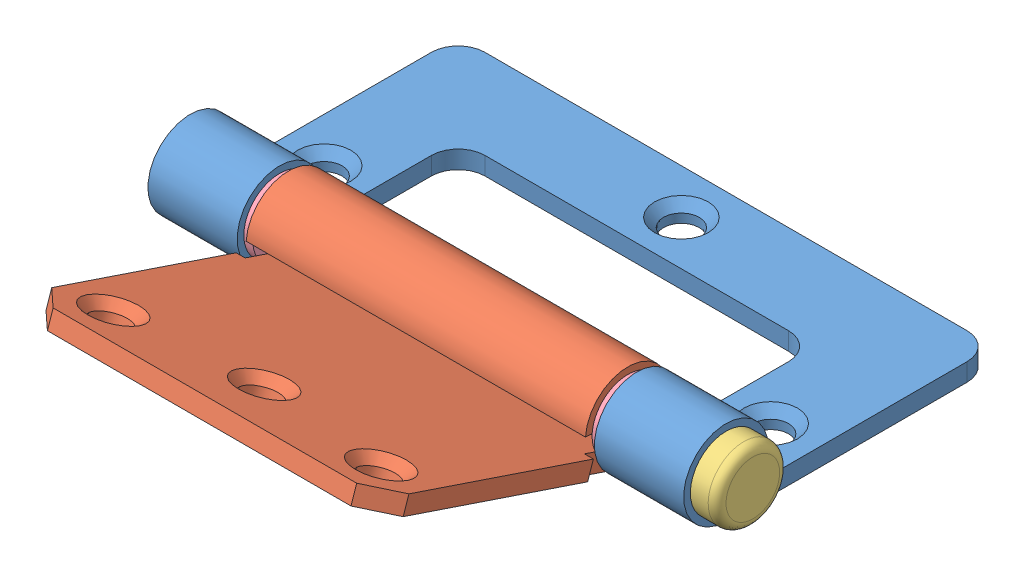
SolidWorks assembly Assembled, configuration Default. Lengths in mm.
Overall size (63 19.77 59).
5 component instances, 4 part files, 9 mates.
Components (placement in the parent):
- 1.Hinge A-1: 1.Hinge A [Default] at (21.0081 35.7241 39.5464) size (60 9.5 34.75)
- 2.Hinge B-1: 2.Hinge B [Default] at (21.0081 40.4917 69.1663) x (-1 0 0) z (0 -0.318898 -0.947789) size (40 9.5 33.75)
- 4.Pin-1: 4.Pin [Default] at (-8.9919 38.4741 54.5464) x (0 0.999658 -0.026144) z (0 -0.026144 -0.999658) size (8 63 8)
- 3.Washer-9: 3.Washer [Default] at (2.0081 38.4741 54.5464) x (0 0.954216 -0.299118) z (0 0.299118 0.954216) size (8 1 8)
- 3.Washer-10: 3.Washer [Default] at (41.0081 38.4741 54.5464) x (0 0.989572 -0.144041) z (0 0.144041 0.989572) size (8 1 8)
Mates (geometry in assembly coordinates):
- Concentric1: concentric anti-aligned: cylinder of 1.Hinge A-1 through (51.0081 38.4741 54.5464) axis (1 0 0) radius 2.75; cylinder of 2.Hinge B-1 through (2.0081 38.4741 54.5464) axis (-1 0 0) radius 2.75
- Width1: width anti-aligned: plane of 1.Hinge A-1 through (51.0081 33.7241 54.5464) normal (1 0 0); plane of 2.Hinge B-1 through (-8.9919 33.7241 54.5464) normal (-1 0 0); plane of 1.Hinge A-1 through (41.0081 33.9721 56.0611) normal (1 0 0); plane of 2.Hinge B-1 through (1.0081 33.9721 56.0611) normal (-1 0 0)
- Concentric2: concentric anti-aligned: cylinder of 1.Hinge A-1 through (51.0081 38.4741 54.5464) axis (1 0 0) radius 2.75; cylinder of 4.Pin-1 through (-8.9919 38.4741 54.5464) axis (-1 0 0) radius 2.75
- Coincident2: coincident anti-aligned: plane of 1.Hinge A-1 through (51.0081 38.4741 54.5464) normal (1 0 0); plane of 4.Pin-1 through (51.0081 34.4755 54.6509) normal (-1 0 0)
- Concentric5: concentric anti-aligned: cylinder of 4.Pin-1 through (-8.9919 38.4741 54.5464) axis (-1 0 0) radius 2.75; cylinder of 3.Washer-9 through (1.0081 38.4741 54.5464) axis (1 0 0) radius 2.75
- Coincident7: coincident anti-aligned: plane of 2.Hinge B-1 through (2.0081 38.4741 54.5464) normal (-1 0 0); plane of 3.Washer-9 through (2.0081 38.4741 54.5464) normal (1 0 0)
- Concentric6: concentric anti-aligned: cylinder of 4.Pin-1 through (-8.9919 38.4741 54.5464) axis (-1 0 0) radius 2.75; cylinder of 3.Washer-10 through (40.0081 38.4741 54.5464) axis (1 0 0) radius 2.75
- Coincident8: coincident anti-aligned: plane of 1.Hinge A-1 through (41.0081 38.4741 54.5464) normal (-1 0 0); plane of 3.Washer-10 through (41.0081 38.4741 54.5464) normal (1 0 0)
- LimitAngle2: limit planar angle = 2.817027 rad anti-aligned: plane of 2.Hinge B-1 through (21.0081 40.4917 69.1663) normal (0 0.947789 -0.318898); plane of 1.Hinge A-1 through (-5.9919 35.7241 27.5464) normal (0 1 0)
